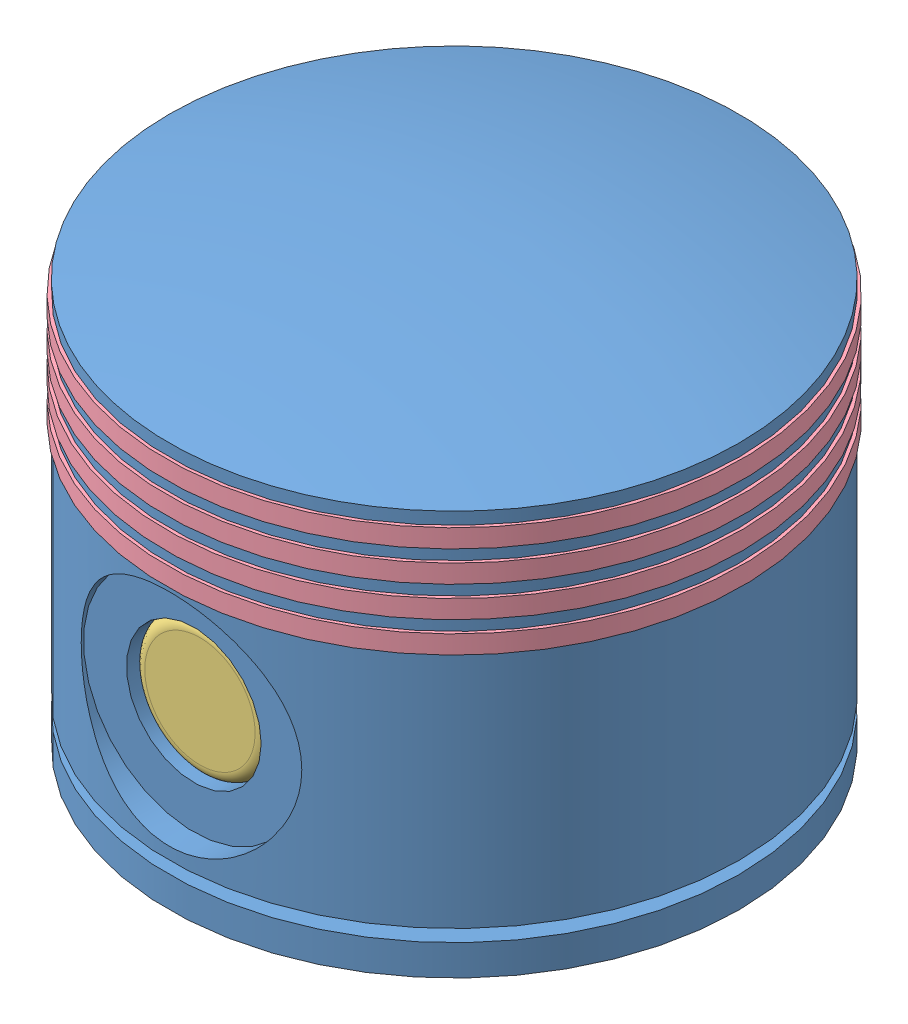
SolidWorks assembly piston assembly, configuration Default. Lengths in mm.
Overall size (111.75 71.81 111.75).
8 component instances, 4 part files, 14 mates.
Components (placement in the parent):
- piston-2: piston [Default] at (-18.3187 26.7763 89.758) size (93 71.81 93)
- piston_pin-2: piston_pin [Default] at (-18.3187 53.7763 88.258) x (0.998755 -0.049893 0) z (-0.049893 -0.998755 0) size (22 80 22)
- piston_plug-3: piston_plug [Default] at (-18.3187 53.7763 116.258) x (1 0 0) z (0 -1 0) size (22 15 22)
- piston_ring-2: piston_ring [Default] at (-18.3187 74.2763 89.758) size (94 3 94)
- piston_plug-4: piston_plug [Default] at (-18.3187 53.7763 60.258) x (-0.837169 0.546944 0) z (-0.546944 -0.837169 0) size (22 15 22)
- piston_ring-3: piston_ring [Default] at (-18.3187 89.2763 89.758) size (94 3 94)
- piston_ring-6: piston_ring [Default] at (-18.3187 79.2763 89.758) x (0.977406 0 -0.211373) z (0.211373 0 0.977406) size (94 3 94)
- piston_ring-7: piston_ring [Default] at (-18.3187 84.2763 89.758) size (94 3 94)
Mates (geometry in assembly coordinates):
- Concentric13: concentric aligned: circle of piston_pin-2; circle of piston_plug-3
- Coincident19: coincident anti-aligned: plane of piston_pin-2 through (-18.3187 53.7763 128.258) normal (0 0 1); plane of piston_plug-3 through (-23.8187 53.7763 128.258) normal (0 0 -1)
- Concentric14: concentric anti-aligned: circle of piston_pin-2; circle of piston_plug-4
- Coincident20: coincident anti-aligned: plane of piston_pin-2 through (-18.3187 53.7763 48.258) normal (0 0 -1); plane of piston_plug-4 through (-13.7143 50.7681 48.258) normal (0 0 1)
- Concentric16: concentric aligned: circle of piston-2; circle of piston_pin-2
- Tangent4: tangent: circle of piston-2; torus of piston_plug-4
- Concentric19: concentric aligned: circle of piston-2; circle of piston_ring-6
- Concentric20: concentric aligned: circle of piston_ring-3; circle of piston_ring-7
- Concentric21: concentric aligned: circle of piston_ring-2; circle of piston_ring-3
- Concentric22: concentric aligned: circle of piston_ring-2; circle of piston_ring-6
- Coincident27: coincident anti-aligned: plane of piston-2 through (-18.3187 90.7763 89.758) normal (0 -1 0); plane of piston_ring-3 through (-18.3187 90.7763 89.758) normal (0 1 0)
- Coincident28: coincident anti-aligned: plane of piston-2 through (-18.3187 85.7763 89.758) normal (0 -1 0); plane of piston_ring-7 through (-18.3187 85.7763 89.758) normal (0 1 0)
- Coincident29: coincident anti-aligned: plane of piston-2 through (-18.3187 80.7763 89.758) normal (0 -1 0); plane of piston_ring-6 through (-18.3187 80.7763 89.758) normal (0 1 0)
- Coincident30: coincident anti-aligned: plane of piston-2 through (-18.3187 75.7763 89.758) normal (0 -1 0); plane of piston_ring-2 through (-18.3187 75.7763 89.758) normal (0 1 0)
